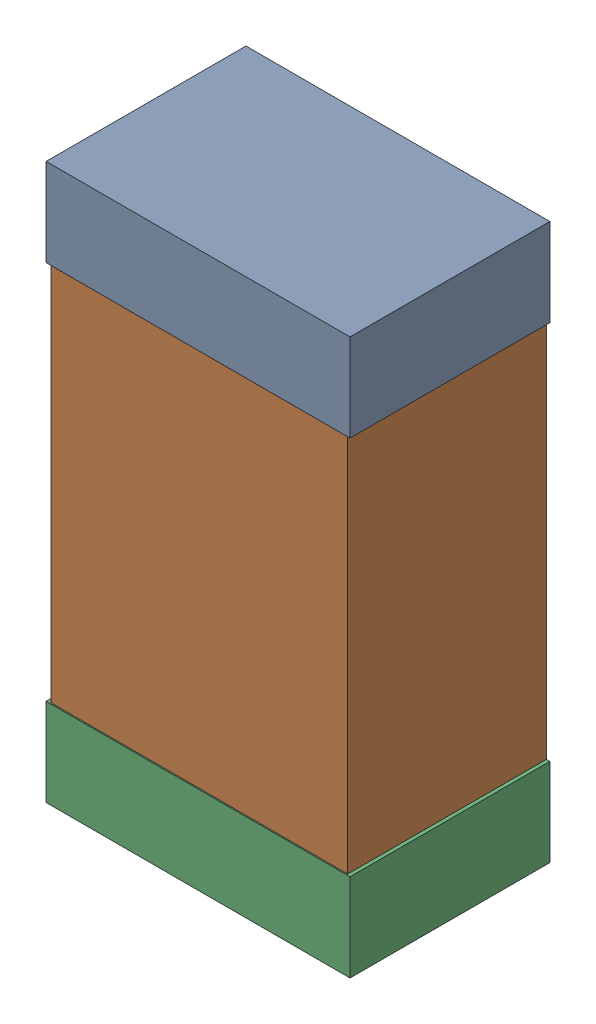
SolidWorks assembly C8Kanaloa_v2.0.0_Power, configuration Default. Lengths in mm.
Overall size (1.3 2.38 0.85).
6 component instances, 2 part files, 0 mates.
Components (placement in the parent):
- 330415056-1: 330415056 [Default] at (98.1322 92.8992 0) size (1.3 0.38 0.85)
  - Extruded_2-1: Extruded_2 [Default] at origin size (1.3 0.38 0.85)
- 352877008-1: 352877008 [Default] at (98.1322 91.8992 0) size (1.27 2.2 0.85)
  - Extruded_3-1: Extruded_3 [Default] at origin size (1.27 2.2 0.85)
- 330415056-2: 330415056 [Default] at (98.1322 90.8992 0) size (1.3 0.38 0.85)
  - Extruded_2-1: Extruded_2 [Default] at origin size (1.3 0.38 0.85)
